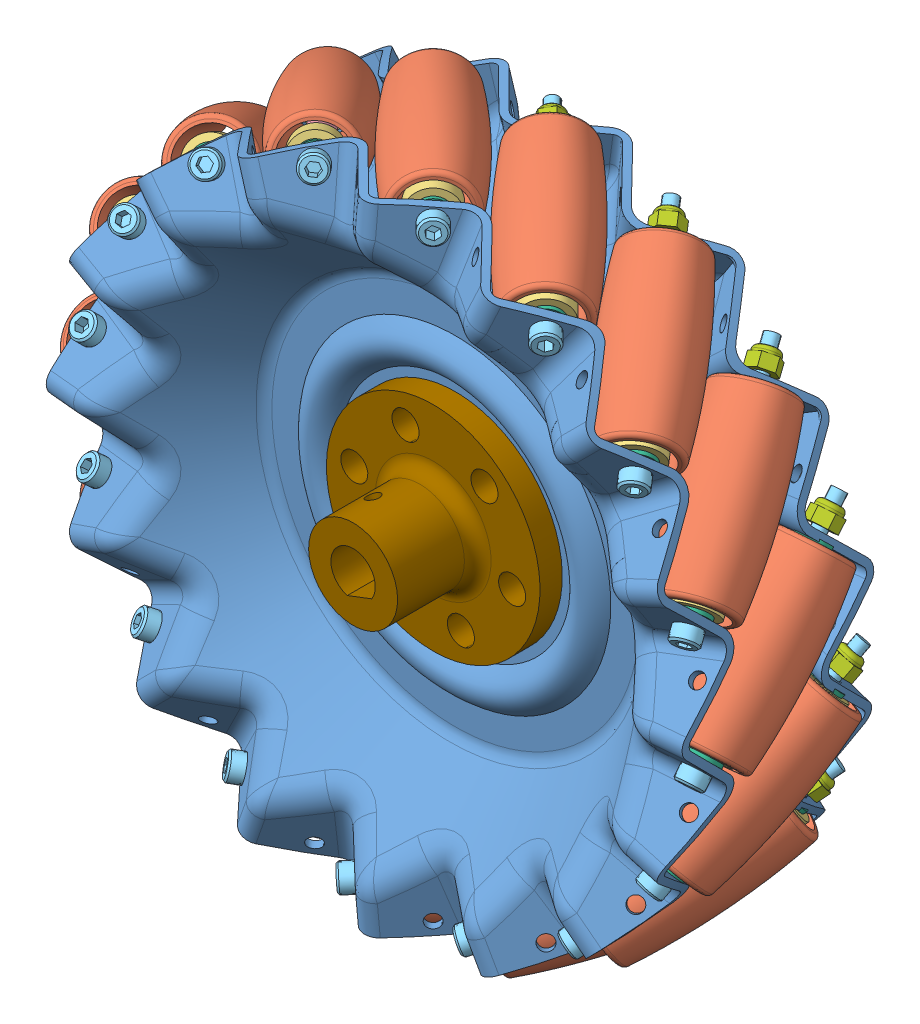
SolidWorks assembly 麦轮（右）, configuration 默认. Lengths in mm.
Overall size (166.55 166.55 53.71).
164 component instances, 10 part files, 25 mates.
Components (placement in the parent):
- 麦轮钣金-4: 麦轮钣金 [默认] at (-28.4888 0.9465 132.4522) size (142.88 142.88 24.05)
- 麦轮钣金-5: 麦轮钣金 [默认] at (-28.4888 0.9465 129.2518) x (-0.182456 0.983214 0) z (0 0 -1) size (142.88 142.88 24.05)
- 滚花橡胶轮组装-1: 滚花橡胶轮组装 [默认] at (-11.7664 74.8711 111.2311) x (-0.611613 0.360957 0.704017) z (0.544848 -0.453042 0.705615) size (18.5 18.5 53)
  - 滚花橡胶轮外-1: 滚花橡胶轮外 [默认] at (-9.896 1.7835 38.5971) size (18.5 18.5 38)
  - 滚花铝柱-1: 滚花铝柱 [默认] at (-9.896 1.7835 38) x (0.787441 0.61639 0) z (-0.61639 0.787441 0) size (13 38 13) (hidden)
  - 轴承5X10X4-1: 轴承5X10X4 [默认] at (-9.896 1.7835 55) x (0.442498 0.896769 0) z (-0.896769 0.442498 0) size (10 4 10)
  - 轴承5X10X4-2: 轴承5X10X4 [默认] at (-9.896 1.7835 21) x (0.442498 0.896769 0) z (-0.896769 0.442498 0) size (10 4 10)
  - 铜管3X5-1: 铜管3X5 [默认] at (-9.896 1.7835 38) x (0.823254 0.567673 0) z (-0.567673 0.823254 0) size (5 38 5)
  - 螺丝-1: 螺丝 [默认] at (-9.896 1.7835 59.6) x (-0.462621 0.886556 0) z (0 0 1) size (5.5 5.5 53)
  - 垫片-1: 垫片 [默认] at (-9.896 1.7835 57) x (1 0 0) z (0 -1 0) size (7 0.8 7)
  - 垫片-2: 垫片 [默认] at (-9.896 1.7835 19) x (0.746862 -0.664979 0) z (0.664979 0.746862 0) size (7 0.8 7)
  - 螺母-1: 螺母 [默认] at (-9.896 1.7835 16.2) x (-0.766894 0.641774 0) z (0 0 -1) size (6.35 5.5 4.25)
- 滚花橡胶轮组装-2: 滚花橡胶轮组装 [默认] at (27.0215 56.1049 99.7367) x (0.936151 0.121324 -0.330002) z (0.330002 -0.627061 0.705615) size (18.5 18.5 53)
  - 滚花橡胶轮外-1: 滚花橡胶轮外 [默认] at (-9.896 1.7835 38.5971) size (18.5 18.5 38)
  - 滚花铝柱-1: 滚花铝柱 [默认] at (-9.896 1.7835 38) x (0.787441 0.61639 0) z (-0.61639 0.787441 0) size (13 38 13) (hidden)
  - 轴承5X10X4-1: 轴承5X10X4 [默认] at (-9.896 1.7835 55) x (0.442498 0.896769 0) z (-0.896769 0.442498 0) size (10 4 10)
  - 轴承5X10X4-2: 轴承5X10X4 [默认] at (-9.896 1.7835 21) x (0.442498 0.896769 0) z (-0.896769 0.442498 0) size (10 4 10)
  - 铜管3X5-1: 铜管3X5 [默认] at (-9.896 1.7835 38) x (0.823254 0.567673 0) z (-0.567673 0.823254 0) size (5 38 5)
  - 螺丝-1: 螺丝 [默认] at (-9.896 1.7835 59.6) x (-0.462621 0.886556 0) z (0 0 1) size (5.5 5.5 53)
  - 垫片-1: 垫片 [默认] at (-9.896 1.7835 57) x (1 0 0) z (0 -1 0) size (7 0.8 7)
  - 垫片-2: 垫片 [默认] at (-9.896 1.7835 19) x (0.746862 -0.664979 0) z (0.664979 0.746862 0) size (7 0.8 7)
  - 螺母-1: 螺母 [默认] at (-9.896 1.7835 16.2) x (-0.766894 0.641774 0) z (0 0 -1) size (6.35 5.5 4.25)
- 滚花橡胶轮组装-3: 滚花橡胶轮组装 [默认] at (40.6784 28.3806 97.7508) x (0.648729 -0.507452 -0.567136) z (0.064917 -0.705615 0.705615) size (18.5 18.5 53)
  - 滚花橡胶轮外-1: 滚花橡胶轮外 [默认] at (-9.896 1.7835 38.5971) size (18.5 18.5 38)
  - 滚花铝柱-1: 滚花铝柱 [默认] at (-9.896 1.7835 38) x (0.787441 0.61639 0) z (-0.61639 0.787441 0) size (13 38 13) (hidden)
  - 轴承5X10X4-1: 轴承5X10X4 [默认] at (-9.896 1.7835 55) x (0.442498 0.896769 0) z (-0.896769 0.442498 0) size (10 4 10)
  - 轴承5X10X4-2: 轴承5X10X4 [默认] at (-9.896 1.7835 21) x (0.442498 0.896769 0) z (-0.896769 0.442498 0) size (10 4 10)
  - 铜管3X5-1: 铜管3X5 [默认] at (-9.896 1.7835 38) x (0.823254 0.567673 0) z (-0.567673 0.823254 0) size (5 38 5)
  - 螺丝-1: 螺丝 [默认] at (-9.896 1.7835 59.6) x (-0.462621 0.886556 0) z (0 0 1) size (5.5 5.5 53)
  - 垫片-1: 垫片 [默认] at (-9.896 1.7835 57) x (1 0 0) z (0 -1 0) size (7 0.8 7)
  - 垫片-2: 垫片 [默认] at (-9.896 1.7835 19) x (0.746862 -0.664979 0) z (0.664979 0.746862 0) size (7 0.8 7)
  - 螺母-1: 螺母 [默认] at (-9.896 1.7835 16.2) x (-0.766894 0.641774 0) z (0 0 -1) size (6.35 5.5 4.25)
- 滚花橡胶轮组装-4: 滚花橡胶轮组装 [默认] at (53.3201 5.2227 104.8515) x (0.974131 -0.083344 0.210052) z (-0.210052 -0.676746 0.705615) size (18.5 18.5 53)
  - 滚花橡胶轮外-1: 滚花橡胶轮外 [默认] at (-9.896 1.7835 38.5971) size (18.5 18.5 38)
  - 滚花铝柱-1: 滚花铝柱 [默认] at (-9.896 1.7835 38) x (0.787441 0.61639 0) z (-0.61639 0.787441 0) size (13 38 13) (hidden)
  - 轴承5X10X4-1: 轴承5X10X4 [默认] at (-9.896 1.7835 55) x (0.442498 0.896769 0) z (-0.896769 0.442498 0) size (10 4 10)
  - 轴承5X10X4-2: 轴承5X10X4 [默认] at (-9.896 1.7835 21) x (0.442498 0.896769 0) z (-0.896769 0.442498 0) size (10 4 10)
  - 铜管3X5-1: 铜管3X5 [默认] at (-9.896 1.7835 38) x (0.823254 0.567673 0) z (-0.567673 0.823254 0) size (5 38 5)
  - 螺丝-1: 螺丝 [默认] at (-9.896 1.7835 59.6) x (-0.462621 0.886556 0) z (0 0 1) size (5.5 5.5 53)
  - 垫片-1: 垫片 [默认] at (-9.896 1.7835 57) x (1 0 0) z (0 -1 0) size (7 0.8 7)
  - 垫片-2: 垫片 [默认] at (-9.896 1.7835 19) x (0.746862 -0.664979 0) z (0.664979 0.746862 0) size (7 0.8 7)
  - 螺母-1: 螺母 [默认] at (-9.896 1.7835 16.2) x (-0.766894 0.641774 0) z (0 0 -1) size (6.35 5.5 4.25)
- 滚花橡胶轮组装-6: 滚花橡胶轮组装 [默认] at (49.4638 -23.6017 107.4914) x (0.879664 -0.144722 0.453042) z (-0.453042 -0.544848 0.705615) size (18.5 18.5 53)
  - 滚花橡胶轮外-1: 滚花橡胶轮外 [默认] at (-9.896 1.7835 38.5971) size (18.5 18.5 38)
  - 滚花铝柱-1: 滚花铝柱 [默认] at (-9.896 1.7835 38) x (0.787441 0.61639 0) z (-0.61639 0.787441 0) size (13 38 13) (hidden)
  - 轴承5X10X4-1: 轴承5X10X4 [默认] at (-9.896 1.7835 55) x (0.442498 0.896769 0) z (-0.896769 0.442498 0) size (10 4 10)
  - 轴承5X10X4-2: 轴承5X10X4 [默认] at (-9.896 1.7835 21) x (0.442498 0.896769 0) z (-0.896769 0.442498 0) size (10 4 10)
  - 铜管3X5-1: 铜管3X5 [默认] at (-9.896 1.7835 38) x (0.823254 0.567673 0) z (-0.567673 0.823254 0) size (5 38 5)
  - 螺丝-1: 螺丝 [默认] at (-9.896 1.7835 59.6) x (-0.462621 0.886556 0) z (0 0 1) size (5.5 5.5 53)
  - 垫片-1: 垫片 [默认] at (-9.896 1.7835 57) x (1 0 0) z (0 -1 0) size (7 0.8 7)
  - 垫片-2: 垫片 [默认] at (-9.896 1.7835 19) x (0.746862 -0.664979 0) z (0.664979 0.746862 0) size (7 0.8 7)
  - 螺母-1: 螺母 [默认] at (-9.896 1.7835 16.2) x (-0.766894 0.641774 0) z (0 0 -1) size (6.35 5.5 4.25)
- 滚花橡胶轮组装-7: 滚花橡胶轮组装 [默认] at (34.7976 -48.3203 109.5966) x (0.769464 -0.121324 0.627061) z (-0.627061 -0.330002 0.705615) size (18.5 18.5 53)
  - 滚花橡胶轮外-1: 滚花橡胶轮外 [默认] at (-9.896 1.7835 38.5971) size (18.5 18.5 38)
  - 滚花铝柱-1: 滚花铝柱 [默认] at (-9.896 1.7835 38) x (0.787441 0.61639 0) z (-0.61639 0.787441 0) size (13 38 13) (hidden)
  - 轴承5X10X4-1: 轴承5X10X4 [默认] at (-9.896 1.7835 55) x (0.442498 0.896769 0) z (-0.896769 0.442498 0) size (10 4 10)
  - 轴承5X10X4-2: 轴承5X10X4 [默认] at (-9.896 1.7835 21) x (0.442498 0.896769 0) z (-0.896769 0.442498 0) size (10 4 10)
  - 铜管3X5-1: 铜管3X5 [默认] at (-9.896 1.7835 38) x (0.823254 0.567673 0) z (-0.567673 0.823254 0) size (5 38 5)
  - 螺丝-1: 螺丝 [默认] at (-9.896 1.7835 59.6) x (-0.462621 0.886556 0) z (0 0 1) size (5.5 5.5 53)
  - 垫片-1: 垫片 [默认] at (-9.896 1.7835 57) x (1 0 0) z (0 -1 0) size (7 0.8 7)
  - 垫片-2: 垫片 [默认] at (-9.896 1.7835 19) x (0.746862 -0.664979 0) z (0.664979 0.746862 0) size (7 0.8 7)
  - 螺母-1: 螺母 [默认] at (-9.896 1.7835 16.2) x (-0.766894 0.641774 0) z (0 0 -1) size (6.35 5.5 4.25)
- 滚花橡胶轮组装-8: 滚花橡胶轮组装 [默认] at (11.9043 -65.198 110.9878) x (0.708086 -0.026856 0.705615) z (-0.705615 -0.064917 0.705615) size (18.5 18.5 53)
  - 滚花橡胶轮外-1: 滚花橡胶轮外 [默认] at (-9.896 1.7835 38.5971) size (18.5 18.5 38)
  - 滚花铝柱-1: 滚花铝柱 [默认] at (-9.896 1.7835 38) x (0.787441 0.61639 0) z (-0.61639 0.787441 0) size (13 38 13) (hidden)
  - 轴承5X10X4-1: 轴承5X10X4 [默认] at (-9.896 1.7835 55) x (0.442498 0.896769 0) z (-0.896769 0.442498 0) size (10 4 10)
  - 轴承5X10X4-2: 轴承5X10X4 [默认] at (-9.896 1.7835 21) x (0.442498 0.896769 0) z (-0.896769 0.442498 0) size (10 4 10)
  - 铜管3X5-1: 铜管3X5 [默认] at (-9.896 1.7835 38) x (0.823254 0.567673 0) z (-0.567673 0.823254 0) size (5 38 5)
  - 螺丝-1: 螺丝 [默认] at (-9.896 1.7835 59.6) x (-0.462621 0.886556 0) z (0 0 1) size (5.5 5.5 53)
  - 垫片-1: 垫片 [默认] at (-9.896 1.7835 57) x (1 0 0) z (0 -1 0) size (7 0.8 7)
  - 垫片-2: 垫片 [默认] at (-9.896 1.7835 19) x (0.746862 -0.664979 0) z (0.664979 0.746862 0) size (7 0.8 7)
  - 螺母-1: 螺母 [默认] at (-9.896 1.7835 16.2) x (-0.766894 0.641774 0) z (0 0 -1) size (6.35 5.5 4.25)
- 滚花橡胶轮组装-9: 滚花橡胶轮组装 [默认] at (-20.4065 -80.021 108.2514) x (0.291286 -0.803832 0.518658) z (-0.676746 0.210052 0.705615) size (18.5 18.5 53)
  - 滚花橡胶轮外-1: 滚花橡胶轮外 [默认] at (-9.896 1.7835 38.5971) size (18.5 18.5 38)
  - 滚花铝柱-1: 滚花铝柱 [默认] at (-9.896 1.7835 38) x (0.787441 0.61639 0) z (-0.61639 0.787441 0) size (13 38 13) (hidden)
  - 轴承5X10X4-1: 轴承5X10X4 [默认] at (-9.896 1.7835 55) x (0.442498 0.896769 0) z (-0.896769 0.442498 0) size (10 4 10)
  - 轴承5X10X4-2: 轴承5X10X4 [默认] at (-9.896 1.7835 21) x (0.442498 0.896769 0) z (-0.896769 0.442498 0) size (10 4 10)
  - 铜管3X5-1: 铜管3X5 [默认] at (-9.896 1.7835 38) x (0.823254 0.567673 0) z (-0.567673 0.823254 0) size (5 38 5)
  - 螺丝-1: 螺丝 [默认] at (-9.896 1.7835 59.6) x (-0.462621 0.886556 0) z (0 0 1) size (5.5 5.5 53)
  - 垫片-1: 垫片 [默认] at (-9.896 1.7835 57) x (1 0 0) z (0 -1 0) size (7 0.8 7)
  - 垫片-2: 垫片 [默认] at (-9.896 1.7835 19) x (0.746862 -0.664979 0) z (0.664979 0.746862 0) size (7 0.8 7)
  - 螺母-1: 螺母 [默认] at (-9.896 1.7835 16.2) x (-0.766894 0.641774 0) z (0 0 -1) size (6.35 5.5 4.25)
- 滚花橡胶轮组装-10: 滚花橡胶轮组装 [默认] at (-46.4094 -74.3284 110.8897) x (0.497758 -0.502453 0.70695) z (-0.544848 0.453042 0.705615) size (18.5 18.5 53)
  - 滚花橡胶轮外-1: 滚花橡胶轮外 [默认] at (-9.896 1.7835 38.5971) size (18.5 18.5 38)
  - 滚花铝柱-1: 滚花铝柱 [默认] at (-9.896 1.7835 38) x (0.787441 0.61639 0) z (-0.61639 0.787441 0) size (13 38 13) (hidden)
  - 轴承5X10X4-1: 轴承5X10X4 [默认] at (-9.896 1.7835 55) x (0.442498 0.896769 0) z (-0.896769 0.442498 0) size (10 4 10)
  - 轴承5X10X4-2: 轴承5X10X4 [默认] at (-9.896 1.7835 21) x (0.442498 0.896769 0) z (-0.896769 0.442498 0) size (10 4 10)
  - 铜管3X5-1: 铜管3X5 [默认] at (-9.896 1.7835 38) x (0.823254 0.567673 0) z (-0.567673 0.823254 0) size (5 38 5)
  - 螺丝-1: 螺丝 [默认] at (-9.896 1.7835 59.6) x (-0.462621 0.886556 0) z (0 0 1) size (5.5 5.5 53)
  - 垫片-1: 垫片 [默认] at (-9.896 1.7835 57) x (1 0 0) z (0 -1 0) size (7 0.8 7)
  - 垫片-2: 垫片 [默认] at (-9.896 1.7835 19) x (0.746862 -0.664979 0) z (0.664979 0.746862 0) size (7 0.8 7)
  - 螺母-1: 螺母 [默认] at (-9.896 1.7835 16.2) x (-0.766894 0.641774 0) z (0 0 -1) size (6.35 5.5 4.25)
- 滚花橡胶轮组装-18: 滚花橡胶轮组装 [默认] at (-41.329 75.6433 111.2311) x (-0.703189 0.099427 0.704017) z (0.676746 -0.210052 0.705615) size (18.5 18.5 53)
  - 滚花橡胶轮外-1: 滚花橡胶轮外 [默认] at (-9.896 1.7835 38.5971) size (18.5 18.5 38)
  - 滚花铝柱-1: 滚花铝柱 [默认] at (-9.896 1.7835 38) x (0.787441 0.61639 0) z (-0.61639 0.787441 0) size (13 38 13) (hidden)
  - 轴承5X10X4-1: 轴承5X10X4 [默认] at (-9.896 1.7835 55) x (0.442498 0.896769 0) z (-0.896769 0.442498 0) size (10 4 10)
  - 轴承5X10X4-2: 轴承5X10X4 [默认] at (-9.896 1.7835 21) x (0.442498 0.896769 0) z (-0.896769 0.442498 0) size (10 4 10)
  - 铜管3X5-1: 铜管3X5 [默认] at (-9.896 1.7835 38) x (0.823254 0.567673 0) z (-0.567673 0.823254 0) size (5 38 5)
  - 螺丝-1: 螺丝 [默认] at (-9.896 1.7835 59.6) x (-0.462621 0.886556 0) z (0 0 1) size (5.5 5.5 53)
  - 垫片-1: 垫片 [默认] at (-9.896 1.7835 57) x (1 0 0) z (0 -1 0) size (7 0.8 7)
  - 垫片-2: 垫片 [默认] at (-9.896 1.7835 19) x (0.746862 -0.664979 0) z (0.664979 0.746862 0) size (7 0.8 7)
  - 螺母-1: 螺母 [默认] at (-9.896 1.7835 16.2) x (-0.766894 0.641774 0) z (0 0 -1) size (6.35 5.5 4.25)
- 滚花橡胶轮组装-19: 滚花橡胶轮组装 [默认] at (-68.9368 65.0436 111.2311) x (-0.687711 -0.17724 0.704017) z (0.705615 0.064917 0.705615) size (18.5 18.5 53)
  - 滚花橡胶轮外-1: 滚花橡胶轮外 [默认] at (-9.896 1.7835 38.5971) size (18.5 18.5 38)
  - 滚花铝柱-1: 滚花铝柱 [默认] at (-9.896 1.7835 38) x (0.787441 0.61639 0) z (-0.61639 0.787441 0) size (13 38 13) (hidden)
  - 轴承5X10X4-1: 轴承5X10X4 [默认] at (-9.896 1.7835 55) x (0.442498 0.896769 0) z (-0.896769 0.442498 0) size (10 4 10)
  - 轴承5X10X4-2: 轴承5X10X4 [默认] at (-9.896 1.7835 21) x (0.442498 0.896769 0) z (-0.896769 0.442498 0) size (10 4 10)
  - 铜管3X5-1: 铜管3X5 [默认] at (-9.896 1.7835 38) x (0.823254 0.567673 0) z (-0.567673 0.823254 0) size (5 38 5)
  - 螺丝-1: 螺丝 [默认] at (-9.896 1.7835 59.6) x (-0.462621 0.886556 0) z (0 0 1) size (5.5 5.5 53)
  - 垫片-1: 垫片 [默认] at (-9.896 1.7835 57) x (1 0 0) z (0 -1 0) size (7 0.8 7)
  - 垫片-2: 垫片 [默认] at (-9.896 1.7835 19) x (0.746862 -0.664979 0) z (0.664979 0.746862 0) size (7 0.8 7)
  - 螺母-1: 螺母 [默认] at (-9.896 1.7835 16.2) x (-0.766894 0.641774 0) z (0 0 -1) size (6.35 5.5 4.25)
- 滚花橡胶轮组装-20: 滚花橡胶轮组装 [默认] at (-90.3868 44.6856 111.2311) x (-0.567535 -0.426924 0.704017) z (0.627061 0.330002 0.705615) size (18.5 18.5 53)
  - 滚花橡胶轮外-1: 滚花橡胶轮外 [默认] at (-9.896 1.7835 38.5971) size (18.5 18.5 38)
  - 滚花铝柱-1: 滚花铝柱 [默认] at (-9.896 1.7835 38) x (0.787441 0.61639 0) z (-0.61639 0.787441 0) size (13 38 13) (hidden)
  - 轴承5X10X4-1: 轴承5X10X4 [默认] at (-9.896 1.7835 55) x (0.442498 0.896769 0) z (-0.896769 0.442498 0) size (10 4 10)
  - 轴承5X10X4-2: 轴承5X10X4 [默认] at (-9.896 1.7835 21) x (0.442498 0.896769 0) z (-0.896769 0.442498 0) size (10 4 10)
  - 铜管3X5-1: 铜管3X5 [默认] at (-9.896 1.7835 38) x (0.823254 0.567673 0) z (-0.567673 0.823254 0) size (5 38 5)
  - 螺丝-1: 螺丝 [默认] at (-9.896 1.7835 59.6) x (-0.462621 0.886556 0) z (0 0 1) size (5.5 5.5 53)
  - 垫片-1: 垫片 [默认] at (-9.896 1.7835 57) x (1 0 0) z (0 -1 0) size (7 0.8 7)
  - 垫片-2: 垫片 [默认] at (-9.896 1.7835 19) x (0.746862 -0.664979 0) z (0.664979 0.746862 0) size (7 0.8 7)
  - 螺母-1: 螺母 [默认] at (-9.896 1.7835 16.2) x (-0.766894 0.641774 0) z (0 0 -1) size (6.35 5.5 4.25)
- 滚花橡胶轮组装-21: 滚花橡胶轮组装 [默认] at (-102.4133 17.6688 111.2311) x (-0.360957 -0.611613 0.704017) z (0.453042 0.544848 0.705615) size (18.5 18.5 53)
  - 滚花橡胶轮外-1: 滚花橡胶轮外 [默认] at (-9.896 1.7835 38.5971) size (18.5 18.5 38)
  - 滚花铝柱-1: 滚花铝柱 [默认] at (-9.896 1.7835 38) x (0.787441 0.61639 0) z (-0.61639 0.787441 0) size (13 38 13) (hidden)
  - 轴承5X10X4-1: 轴承5X10X4 [默认] at (-9.896 1.7835 55) x (0.442498 0.896769 0) z (-0.896769 0.442498 0) size (10 4 10)
  - 轴承5X10X4-2: 轴承5X10X4 [默认] at (-9.896 1.7835 21) x (0.442498 0.896769 0) z (-0.896769 0.442498 0) size (10 4 10)
  - 铜管3X5-1: 铜管3X5 [默认] at (-9.896 1.7835 38) x (0.823254 0.567673 0) z (-0.567673 0.823254 0) size (5 38 5)
  - 螺丝-1: 螺丝 [默认] at (-9.896 1.7835 59.6) x (-0.462621 0.886556 0) z (0 0 1) size (5.5 5.5 53)
  - 垫片-1: 垫片 [默认] at (-9.896 1.7835 57) x (1 0 0) z (0 -1 0) size (7 0.8 7)
  - 垫片-2: 垫片 [默认] at (-9.896 1.7835 19) x (0.746862 -0.664979 0) z (0.664979 0.746862 0) size (7 0.8 7)
  - 螺母-1: 螺母 [默认] at (-9.896 1.7835 16.2) x (-0.766894 0.641774 0) z (0 0 -1) size (6.35 5.5 4.25)
- 滚花橡胶轮组装-22: 滚花橡胶轮组装 [默认] at (-103.1855 -11.8938 111.2311) x (-0.099427 -0.703189 0.704017) z (0.210052 0.676746 0.705615) size (18.5 18.5 53)
  - 滚花橡胶轮外-1: 滚花橡胶轮外 [默认] at (-9.896 1.7835 38.5971) size (18.5 18.5 38)
  - 滚花铝柱-1: 滚花铝柱 [默认] at (-9.896 1.7835 38) x (0.787441 0.61639 0) z (-0.61639 0.787441 0) size (13 38 13) (hidden)
  - 轴承5X10X4-1: 轴承5X10X4 [默认] at (-9.896 1.7835 55) x (0.442498 0.896769 0) z (-0.896769 0.442498 0) size (10 4 10)
  - 轴承5X10X4-2: 轴承5X10X4 [默认] at (-9.896 1.7835 21) x (0.442498 0.896769 0) z (-0.896769 0.442498 0) size (10 4 10)
  - 铜管3X5-1: 铜管3X5 [默认] at (-9.896 1.7835 38) x (0.823254 0.567673 0) z (-0.567673 0.823254 0) size (5 38 5)
  - 螺丝-1: 螺丝 [默认] at (-9.896 1.7835 59.6) x (-0.462621 0.886556 0) z (0 0 1) size (5.5 5.5 53)
  - 垫片-1: 垫片 [默认] at (-9.896 1.7835 57) x (1 0 0) z (0 -1 0) size (7 0.8 7)
  - 垫片-2: 垫片 [默认] at (-9.896 1.7835 19) x (0.746862 -0.664979 0) z (0.664979 0.746862 0) size (7 0.8 7)
  - 螺母-1: 螺母 [默认] at (-9.896 1.7835 16.2) x (-0.766894 0.641774 0) z (0 0 -1) size (6.35 5.5 4.25)
- 滚花橡胶轮组装-23: 滚花橡胶轮组装 [默认] at (-92.5858 -39.5016 111.2311) x (0.17724 -0.687711 0.704017) z (-0.064917 0.705615 0.705615) size (18.5 18.5 53)
  - 滚花橡胶轮外-1: 滚花橡胶轮外 [默认] at (-9.896 1.7835 38.5971) size (18.5 18.5 38)
  - 滚花铝柱-1: 滚花铝柱 [默认] at (-9.896 1.7835 38) x (0.787441 0.61639 0) z (-0.61639 0.787441 0) size (13 38 13) (hidden)
  - 轴承5X10X4-1: 轴承5X10X4 [默认] at (-9.896 1.7835 55) x (0.442498 0.896769 0) z (-0.896769 0.442498 0) size (10 4 10)
  - 轴承5X10X4-2: 轴承5X10X4 [默认] at (-9.896 1.7835 21) x (0.442498 0.896769 0) z (-0.896769 0.442498 0) size (10 4 10)
  - 铜管3X5-1: 铜管3X5 [默认] at (-9.896 1.7835 38) x (0.823254 0.567673 0) z (-0.567673 0.823254 0) size (5 38 5)
  - 螺丝-1: 螺丝 [默认] at (-9.896 1.7835 59.6) x (-0.462621 0.886556 0) z (0 0 1) size (5.5 5.5 53)
  - 垫片-1: 垫片 [默认] at (-9.896 1.7835 57) x (1 0 0) z (0 -1 0) size (7 0.8 7)
  - 垫片-2: 垫片 [默认] at (-9.896 1.7835 19) x (0.746862 -0.664979 0) z (0.664979 0.746862 0) size (7 0.8 7)
  - 螺母-1: 螺母 [默认] at (-9.896 1.7835 16.2) x (-0.766894 0.641774 0) z (0 0 -1) size (6.35 5.5 4.25)
- 滚花橡胶轮组装-24: 滚花橡胶轮组装 [默认] at (-72.2279 -60.9516 111.2311) x (0.426924 -0.567535 0.704017) z (-0.330002 0.627061 0.705615) size (18.5 18.5 53)
  - 滚花橡胶轮外-1: 滚花橡胶轮外 [默认] at (-9.896 1.7835 38.5971) size (18.5 18.5 38)
  - 滚花铝柱-1: 滚花铝柱 [默认] at (-9.896 1.7835 38) x (0.787441 0.61639 0) z (-0.61639 0.787441 0) size (13 38 13) (hidden)
  - 轴承5X10X4-1: 轴承5X10X4 [默认] at (-9.896 1.7835 55) x (0.442498 0.896769 0) z (-0.896769 0.442498 0) size (10 4 10)
  - 轴承5X10X4-2: 轴承5X10X4 [默认] at (-9.896 1.7835 21) x (0.442498 0.896769 0) z (-0.896769 0.442498 0) size (10 4 10)
  - 铜管3X5-1: 铜管3X5 [默认] at (-9.896 1.7835 38) x (0.823254 0.567673 0) z (-0.567673 0.823254 0) size (5 38 5)
  - 螺丝-1: 螺丝 [默认] at (-9.896 1.7835 59.6) x (-0.462621 0.886556 0) z (0 0 1) size (5.5 5.5 53)
  - 垫片-1: 垫片 [默认] at (-9.896 1.7835 57) x (1 0 0) z (0 -1 0) size (7 0.8 7)
  - 垫片-2: 垫片 [默认] at (-9.896 1.7835 19) x (0.746862 -0.664979 0) z (0.664979 0.746862 0) size (7 0.8 7)
  - 螺母-1: 螺母 [默认] at (-9.896 1.7835 16.2) x (-0.766894 0.641774 0) z (0 0 -1) size (6.35 5.5 4.25)
- 电机固定器 2-1: 电机固定器 2 [默认] at (-28.4888 0.9465 126.2518) x (0 0 1) z (-0.768427 0.639938 0) size (3 48 48)
- 电机固定器1-1: 电机固定器1 [默认] at (-28.4888 0.9465 137.4522) x (0 0 -1) z (0.938416 0.345508 0) size (26 48 48)
Mates (geometry in assembly coordinates):
- 同心27: concentric anti-aligned: cylinder of 麦轮钣金-4 through (24.7553 43.6594 144.9053) axis (-0.544848 0.453042 -0.705615) radius 1.6; cylinder of 滚花橡胶轮组装-1/螺丝-1 through (-1.5064 65.496 110.8947) axis (0.544848 -0.453042 0.705615) radius 1.5
- 重合22: coincident anti-aligned: plane of 麦轮钣金-4 through (22.9202 70.2277 163.3806) normal (-0.544848 0.453042 -0.705615); plane of 滚花橡胶轮组装-1/垫片-1 through (24.7553 43.6594 144.9053) normal (0.544848 -0.453042 0.705615)
- 同心28: concentric anti-aligned: cylinder of 麦轮钣金-4 through (37.0479 20.0325 144.9053) axis (-0.330002 0.627061 -0.705615) radius 1.5875; cylinder of 滚花橡胶轮组装-2/螺丝-1 through (21.1418 50.2568 110.8947) axis (0.330002 -0.627061 0.705615) radius 1.5
- 重合23: coincident anti-aligned: plane of 麦轮钣金-4 through (45.5197 45.2807 163.3806) normal (-0.330002 0.627061 -0.705615); plane of 滚花橡胶轮组装-2/垫片-1 through (37.0479 20.0325 144.9053) normal (0.330002 -0.627061 0.705615)
- 同心29: concentric anti-aligned: cylinder of 麦轮钣金-4 through (39.3631 -6.5002 144.9053) axis (-0.064917 0.705615 -0.705615) radius 1.5875; cylinder of 滚花橡胶轮组装-3/螺丝-1 through (36.2341 27.5105 110.8947) axis (0.064917 -0.705615 0.705615) radius 1.5
- 重合24: coincident anti-aligned: plane of 麦轮钣金-4 through (56.8521 13.5841 163.3806) normal (-0.064917 0.705615 -0.705615); plane of 滚花橡胶轮组装-3/垫片-1 through (39.3631 -6.5002 144.9053) normal (0.064917 -0.705615 0.705615)
- 同心30: concentric anti-aligned: cylinder of 麦轮钣金-4 through (31.3485 -31.8991 144.9053) axis (0.210052 0.676746 -0.705615) radius 1.6; cylinder of 滚花橡胶轮组装-4/螺丝-1 through (41.515 0.8553 110.7537) axis (-0.210052 -0.676746 0.705615) radius 1.5
- 重合25: coincident anti-aligned: plane of 麦轮钣金-4 through (54.856 -21.1193 164.5097) normal (-0.210052 -0.676746 0.705615); plane of 滚花橡胶轮组装-4/螺丝-1 through (29.5699 -31.0926 147.4172) normal (0.210052 0.676746 -0.705615)
- 同心31: concentric anti-aligned: cylinder of 麦轮钣金-4 through (14.2242 -52.2976 144.9053) axis (0.453042 0.544848 -0.705615) radius 1.6; cylinder of 滚花橡胶轮组装-6/螺丝-1 through (36.1513 -25.927 110.7537) axis (-0.453042 -0.544848 0.705615) radius 1.5
- 重合26: coincident anti-aligned: plane of 麦轮钣金-4 through (40.0676 -51.3343 164.5097) normal (-0.453042 -0.544848 0.705615); plane of 滚花橡胶轮组装-6/螺丝-1 through (12.0273 -50.9716 146.7865) normal (0.453042 0.544848 -0.705615)
- 同心32: concentric anti-aligned: cylinder of 麦轮钣金-4 through (-9.4028 -64.5902 144.9053) axis (0.627061 0.330002 -0.705615) radius 1.6; cylinder of 滚花橡胶轮组装-7/螺丝-1 through (20.9469 -48.6181 110.7537) axis (-0.627061 -0.330002 0.705615) radius 1.5
- 重合27: coincident anti-aligned: plane of 麦轮钣金-4 through (14.842 -73.5901 164.5097) normal (-0.627061 -0.330002 0.705615); plane of 滚花橡胶轮组装-7/螺丝-1 through (-11.6809 -62.6815 146.0413) normal (0.627061 0.330002 -0.705615)
- 同心33: concentric anti-aligned: cylinder of 麦轮钣金-4 through (-35.9354 -66.9054 144.9053) axis (0.705615 0.064917 -0.705615) radius 1.6; cylinder of 滚花橡胶轮组装-8/螺丝-1 through (-1.9247 -63.7764 110.8947) axis (-0.705615 -0.064917 0.705615) radius 1.5
- 重合28: coincident anti-aligned: plane of 麦轮钣金-4 through (-15.8511 -84.3944 163.3806) normal (0.705615 0.064917 -0.705615); plane of 滚花橡胶轮组装-8/垫片-1 through (-35.9354 -66.9054 144.9053) normal (-0.705615 -0.064917 0.705615)
- 同心34: concentric anti-aligned: cylinder of 麦轮钣金-4 through (-61.3343 -58.8908 144.9053) axis (0.676746 -0.210052 -0.705615) radius 1.6; cylinder of 滚花橡胶轮组装-9/螺丝-1 through (-28.5799 -69.0572 110.7537) axis (-0.676746 0.210052 0.705615) radius 1.5
- 重合29: coincident anti-aligned: plane of 麦轮钣金-4 through (-50.5546 -82.3983 164.5097) normal (-0.676746 0.210052 0.705615); plane of 滚花橡胶轮组装-9/螺丝-1 through (-61.1394 -56.1751 146.5517) normal (0.676746 -0.210052 -0.705615)
- 同心35: concentric anti-aligned: cylinder of 麦轮钣金-4 through (-81.7328 -41.7665 144.9053) axis (0.544848 -0.453042 -0.705615) radius 1.6; cylinder of 滚花橡胶轮组装-10/螺丝-1 through (-55.3622 -63.6936 110.7537) axis (-0.544848 0.453042 0.705615) radius 1.5
- 重合30: coincident anti-aligned: plane of 麦轮钣金-4 through (-80.7696 -67.6098 164.5097) normal (-0.544848 0.453042 0.705615); plane of 滚花橡胶轮组装-10/螺丝-1 through (-81.5927 -38.6069 145.2527) normal (0.544848 -0.453042 -0.705615)
- 同心38: concentric anti-aligned: cylinder of 麦轮钣金-5 through (-28.4888 0.9465 139.2518) axis (0 0 -1) radius 10; circle of 电机固定器1-1
- 重合34: coincident anti-aligned: circle of 麦轮钣金-4; circle of 麦轮钣金-5
- 同心39: concentric aligned: circle of 麦轮钣金-5; circle of 电机固定器1-1
- 重合35: coincident anti-aligned: plane of 麦轮钣金-4 through (-13.9632 73.9715 132.4522) normal (0 0 1); plane of 电机固定器1-1 through (-28.4888 0.9465 132.4522) normal (0 0 -1)
- 同心40: concentric anti-aligned: circle of 麦轮钣金-5; circle of 电机固定器 2-1
- 同心41: concentric anti-aligned: circle of 麦轮钣金-5; circle of 电机固定器 2-1
- 重合38: coincident anti-aligned: plane of 麦轮钣金-5 through (40.6602 28.552 129.2518) normal (0 0 -1); plane of 电机固定器 2-1 through (-28.4888 0.9465 129.2518) normal (0 0 1)
